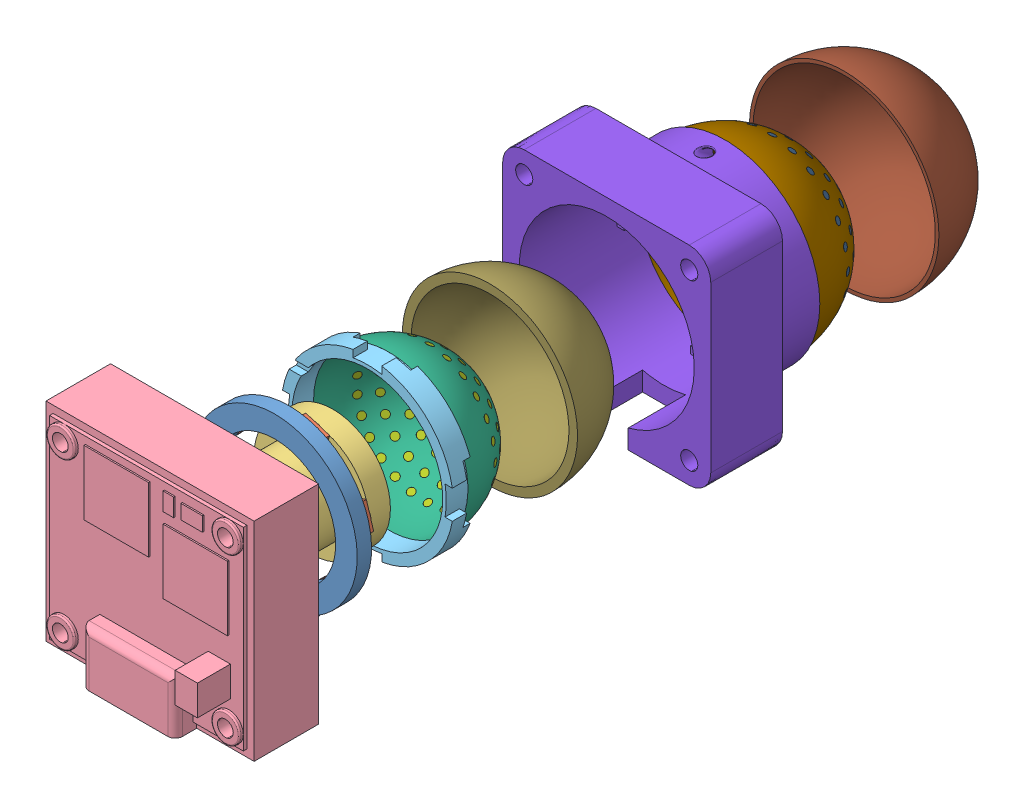
SolidWorks assembly fingertip_v2_assembly_expl, configuration Default. Lengths in mm.
Overall size (34.39 34.39 115.03).
22 component instances, 13 part files, 11 mates.
Components (placement in the parent):
- fingertip_v2-1: fingertip_v2 [Default] at origin size (29 39 42) (hidden)
- led_pcb_assembly-1: led_pcb_assembly [Default] at (14.5 14.5 -26.4135) x (-1 0 0) z (0 -1 0) size (23 5 25.5)
  - pcb_v2-1: pcb_v2 [Default] at origin size (23 5 25.5)
  - led-1: led [Default] at (5.071 2 -6.8216) x (0.662524 0 0.749041) z (-0.749041 0 0.662524) size (3.5 0.7 2.8)
  - led-2: led [Default] at (2.3197 2 11.0131) x (0.934581 0 -0.35575) z (0.35575 0 0.934581) size (3.5 0.7 2.8)
  - led-3: led [Default] at (8.4879 2 0.4525) x (-0.25768 0 0.96623) z (-0.96623 0 -0.25768) size (3.5 0.7 2.8)
  - led-4: led [Default] at (-10.1232 2 -4.9184) x (-0.291837 0 0.956468) z (-0.956468 0 -0.291837) size (3.5 0.7 2.8)
  - led-5: led [Default] at (-4.1707 2 -7.4064) x (0.953699 0 -0.300763) z (0.300763 0 0.953699) size (3.5 0.7 2.8)
  - led-6: led [Default] at (-8.6811 2 7.163) x (0.748631 0 0.662987) z (-0.662987 0 0.748631) size (3.5 0.7 2.8)
- basler_camera_160_assembly-1: basler_camera_160_assembly [Default] at (0 0 -9.0415) x (0 1 0) z (0 0 -1) size (29 29 31.6)
  - basler_lens-1: basler_lens [Default] at (14.5 14.5 8.7) size (16 16 17.8)
  - basler_body_160-1: basler_body_160 [Default] at origin size (29 29 20.1)
- tactile_dome_inner-1: tactile_dome_inner [Default] at (14.5 14.5 -42.3329) x (0 -1 0) z (1 0 0) size (23.66 14 23.66)
  - dome_inner_rigidframe-1: dome_inner_rigidframe [Default] at origin size (23.66 3 23.66)
  - dome_inner_gel-1: dome_inner_gel [Default] at origin size (22 10.99 22)
  - dome_inner_markers-1: dome_inner_markers [Default] at origin size (19.94 6.6 19.91)
- tactile_dome_outer-1: tactile_dome_outer [Default] at (14.5 14.5 -89.1835) x (0 -1 0) z (1 0 0) size (29 29.2 29)
  - dome_outer_rigidframe-1: dome_outer_rigidframe [Default] at origin size (29 16.65 29)
  - dome_outer_gel-1: dome_outer_gel [Default] at origin size (25.4 12.69 25.4)
  - dome_outer_markers-1: dome_outer_markers [Default] at origin size (22.95 7.51 22.91)
- white_difflayer-1: white_difflayer [Default] at (14.5 14.5 -105.775) x (0.926718 -0.375758 0) z (0.375758 0.926718 0) size (26.4 13.2 26.4)
- silicone_betweenlayer-1: silicone_betweenlayer [Default] at (14.5 14.5 -56.4099) x (0.996165 -0.0875 0) z (0.0875 0.996165 0) size (24.4 12.2 24.4)
Mates (geometry in assembly coordinates):
- Concentric1: concentric anti-aligned: cylinder of fingertip_v2-1 through (26 3 5) axis (0 0 -1) radius 1.2; cylinder of basler_camera_160_assembly-1/basler_body_160-1 through (26 3 -24.0415) axis (0 0 1) radius 1.1
- Concentric2: concentric anti-aligned: cylinder of fingertip_v2-1 through (3 26 5) axis (0 0 -1) radius 1.2; cylinder of basler_camera_160_assembly-1/basler_body_160-1 through (3 26 -24.0415) axis (0 0 1) radius 1.1
- Concentric3: concentric aligned: cylinder of led_pcb_assembly-1/pcb_v2-1 through (14.5 14.5 -28.4135) axis (0 0 1) radius 8.5; cylinder of basler_camera_160_assembly-1/basler_body_160-1 through (14.5 14.5 -24.0415) axis (0 0 1) radius 8.1
- Concentric4: concentric anti-aligned: cylinder of basler_camera_160_assembly-1/basler_body_160-1 through (26 3 -24.0415) axis (0 0 1) radius 1.1; cylinder of tactile_dome_outer-1/dome_outer_rigidframe-1 through (26 3 -72.6835) axis (0 0 -1) radius 1.2
- Concentric5: concentric anti-aligned: cylinder of basler_camera_160_assembly-1/basler_body_160-1 through (3 3 -24.0415) axis (0 0 1) radius 1.1; cylinder of tactile_dome_outer-1/dome_outer_rigidframe-1 through (3 3 -72.6835) axis (0 0 -1) radius 1.2
- Concentric6: concentric aligned: cylinder of tactile_dome_inner-1/dome_inner_rigidframe-1 through (14.5 14.5 -39.3329) axis (0 0 -1) radius 10.5; cylinder of tactile_dome_outer-1/dome_outer_rigidframe-1 through (14.5 14.5 -87.1835) axis (0 0 -1) radius 12.2
- Parallel4: parallel anti-aligned: plane of tactile_dome_inner-1/dome_inner_rigidframe-1 through (3.6833 12.5 -39.3329) normal (0 1 0); plane of tactile_dome_outer-1/dome_outer_rigidframe-1 through (2.4335 12.7 -86.1835) normal (0 -1 0)
- Coincident6: coordinate: point of fingertip_v2-1
- Concentric7: concentric anti-aligned: cylinder of tactile_dome_outer-1/dome_outer_rigidframe-1 through (14.5 14.5 -87.1835) axis (0 0 -1) radius 13.2; circle of white_difflayer-1
- Distance1: distance = 2 mm: cylinder of led_pcb_assembly-1/pcb_v2-1 through (13.5 2 -25.1135) axis (0 0 -1) radius 1; plane of tactile_dome_outer-1/dome_outer_rigidframe-1 through (11.5 10 -72.6835) normal (1 0 0)
- Concentric8: concentric anti-aligned: cylinder of tactile_dome_outer-1/dome_outer_rigidframe-1 through (14.5 14.5 -87.1835) axis (0 0 -1) radius 13.2; circle of silicone_betweenlayer-1
